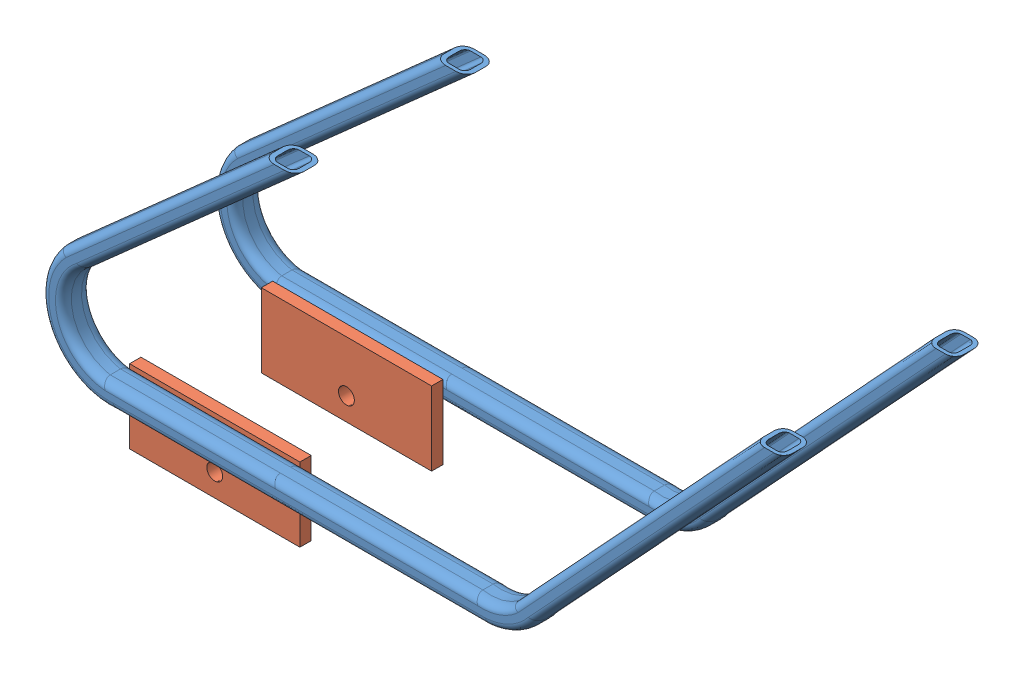
SolidWorks assembly Lower Wheel, configuration Default. Lengths in mm.
Overall size (678.34 305.83 177.58).
4 component instances, 2 part files, 9 mates.
Components (placement in the parent):
- 02-21Lower Wheel Support-1: 02-21Lower Wheel Support [Default] at (-161.3811 20.8246 719.0539) x (1 0 0) z (0 -1 0) size (678.34 26.58 264.21)
- 02-21Lower Wheel Support-2: 02-21Lower Wheel Support [Default] at (-161.3811 20.8246 870.0539) x (1 0 0) z (0 -1 0) size (678.34 26.58 264.21)
- 02-21Wheel Platform-1: 02-21Wheel Platform [Default] at (-243.2393 -2.3689 731.5539) x (1 0 0) z (0 -1 0) size (150 10 65)
- 02-21Wheel Platform-3: 02-21Wheel Platform [Default] at (-243.2393 -2.3689 847.5539) x (1 0 0) z (0 -1 0) size (150 10 65)
Mates (geometry in assembly coordinates):
- Parallel1: parallel aligned: plane of 02-21Lower Wheel Support-1 through (-318.4859 30.1311 714.5539) normal (0 1 0); plane of 02-21Wheel Platform-1 through (-318.2393 30.1311 741.5539) normal (0 1 0)
- Coincident4: coincident anti-aligned: plane of 02-21Lower Wheel Support-1 through (-165.8811 270.8246 731.5539) normal (0 0 1); plane of 02-21Wheel Platform-1 through (-243.2393 -2.3689 731.5539) normal (0 0 -1)
- Coincident5: coincident anti-aligned: line of 02-21Lower Wheel Support-1 through (-318.2393 30.1311 714.5539) axis (0 0 1); line of 02-21Wheel Platform-1 through (-318.2393 30.1311 741.5539) axis (0 0 -1)
- Parallel3: parallel aligned: plane of 02-21Lower Wheel Support-2 through (-318.4859 30.1311 865.5539) normal (0 1 0); plane of 02-21Wheel Platform-3 through (-318.2393 30.1311 857.5539) normal (0 1 0)
- Coincident9: coincident anti-aligned: plane of 02-21Lower Wheel Support-2 through (-165.8811 270.8246 857.5539) normal (0 0 -1); plane of 02-21Wheel Platform-3 through (-243.2393 -2.3689 857.5539) normal (0 0 1)
- Coincident8: coincident anti-aligned: line of 02-21Lower Wheel Support-2 through (-318.2393 30.1311 865.5539) axis (0 0 1); line of 02-21Wheel Platform-3 through (-318.2393 30.1311 857.5539) axis (0 0 -1)
- Coincident11: coincident anti-aligned: circle of Rear Wheel eMotor 600W-1/26x14x8 rolled-1/InnerCage-1; circle of 02-21Wheel Platform-1
- Coincident12: coincident aligned: circle of Rear Wheel eMotor 600W-1/26x14x8 rolled-2/InnerCage-1; circle of 02-21Wheel Platform-3
- Parallel5: parallel aligned: plane of 02-21Lower Wheel Support-1 through (-161.3811 270.8246 719.0539) normal (0 1 0); plane of 02-21Lower Wheel Support-2 through (-161.3811 270.8246 870.0539) normal (0 1 0)
